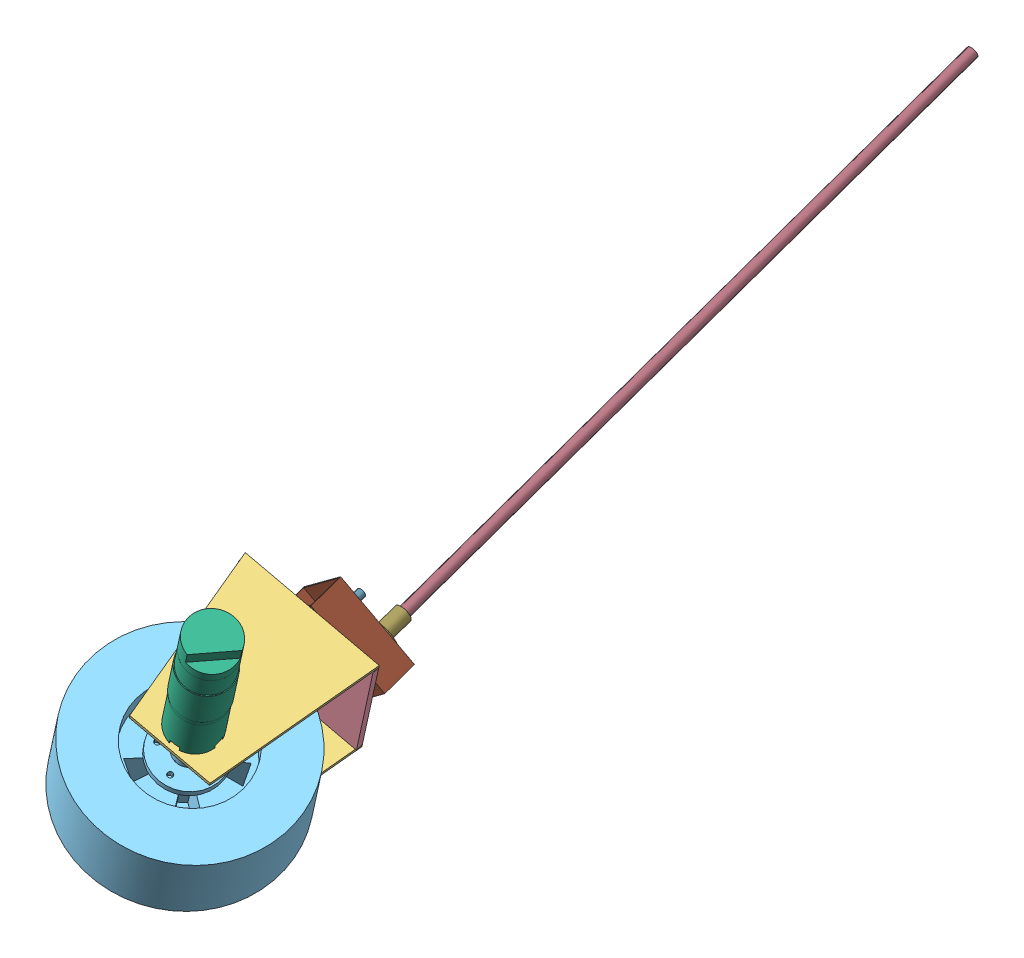
SolidWorks assembly Wheel assembly, configuration Default. Lengths in mm.
Overall size (214.24 272.73 725.65).
17 component instances, 15 part files, 37 mates.
Components (placement in the parent):
- ball bearing-1: ball bearing [Default] at (-218.0914 -76.0667 302.376) x (0.451679 0.074586 -0.889057) z (0.409963 0.867714 0.281074) size (20 20 6)
- bearing block 1-1: bearing block 1 [Default] at (-218.0914 -76.0667 302.376) x (0.911973 -0.384765 -0.142343) z (0.409963 0.867714 0.281074) size (40 40 6)
- Plate 3mm-1: Plate 3mm [Default] at (-215.3243 -77.1542 323.0439) x (0.911973 -0.384765 -0.142343) z (0.409963 0.867714 0.281074) size (100 120 3)
- Plate 5mm-1: Plate 5mm [Default] at (-195.3633 5.0237 228.7976) x (0.409963 0.867714 0.281074) z (-0.015366 0.314687 -0.949071) size (100 100 5)
- Wheel-1: Wheel [Default] at (-206.2025 -50.903 310.5272) x (0.380857 -0.442863 0.811678) z (0.409963 0.867714 0.281074) size (150 150 80)
- Plate 3mm-2: Plate 3mm [Default] at (-173.0982 12.2204 351.9945) x (0.911973 -0.384765 -0.142343) z (0.409963 0.867714 0.281074) size (100 120 3)
- DC Motor-1: DC Motor [Default] at (-171.6426 22.2453 334.2217) x (-0.695966 0.496774 -0.518505) z (-0.409963 -0.867714 -0.281074) size (37.3 37.3 158)
- shaft-1: shaft [Default] at (-220.5512 -81.273 300.6896) x (0.868806 -0.277681 -0.409963) z (0.409963 0.867714 0.281074) size (8 8 50)
- bearing block 1-2: bearing block 1 [Default] at (-195.3633 5.0237 228.7976) x (0.911973 -0.384765 -0.142343) z (0.015366 -0.314687 0.949071) size (40 40 6)
- ball bearing 6 mm-1: ball bearing 6 mm [Default] at (-195.3633 5.0237 228.7976) x (0.999879 0.002481 -0.015366) z (0.015366 -0.314687 0.949071) size (20 20 6)
- Thrust ball bearing-1: Thrust ball bearing [Default] at (-195.5016 7.8559 220.256) x (0.999879 0.002481 -0.015366) z (0.015366 -0.314687 0.949071) size (28 28 9)
- thrust ball bearing upper part-1: thrust ball bearing upper part [Default] at (-195.5938 9.744 214.5615) x (0.643715 -0.723203 -0.250217) z (0.015366 -0.314687 0.949071) size (40 40 5)
- Channel for Rod-1: Channel for Rod [Default] at (-166.8187 -18.8666 191.4384) x (-0.765111 -0.614776 -0.191456) z (-0.643715 0.723203 0.250217) size (50 25 65)
- rod weld mount-1: rod weld mount [Default] at (-179.8851 -0.4689 184.5794) x (0.620168 -0.741551 -0.255919) z (0.784319 0.592516 0.183764) size (30 25 30)
- Steel Shaft-1: Steel Shaft [Default] at (-179.9619 1.1045 179.834) x (0.222387 -0.924333 -0.310085) z (0.974837 0.215826 0.055779) size (8 500 8)
- bolt 6mm-1: bolt 6mm [Default] at (-195.225 2.1915 237.3393) x (0.639836 -0.726304 -0.251182) z (-0.015366 0.314687 -0.949071) size (11.94 10.93 63)
- nut 6mm-1: nut 6mm [Default] at (-196.0548 19.1846 186.0894) x (0.999879 0.002481 -0.015366) z (0.015366 -0.314687 0.949071) size (11.06 11.91 5)
Mates (geometry in assembly coordinates):
- Coincident5: coincident: line of Plate 3mm-1 through (-170.3396 -56.0268 202.8814) axis (-0.911973 0.384765 0.142343); line of Plate 5mm-1 through (-170.3396 -56.0268 202.8814) axis (-0.911973 0.384765 0.142343)
- Coincident6: coincident: plane of Plate 3mm-1 through (-214.0944 -74.551 323.8871) normal (0.409963 0.867714 0.281074); plane of Plate 5mm-1 through (-261.5369 -17.5504 217.1157) normal (-0.409963 -0.867714 -0.281074)
- Width1: width: plane of Plate 3mm-1 through (-261.5369 -17.5504 217.1157) normal (-0.897038 0.327795 0.296432); plane of Plate 3mm-1 through (-170.3396 -56.0268 202.8814) normal (0.902091 -0.431264 0.01562); plane of Plate 5mm-1 through (-170.3396 -56.0268 202.8814) normal (0.911973 -0.384765 -0.142343); plane of Plate 5mm-1 through (-261.5369 -17.5504 217.1157) normal (-0.911973 0.384765 0.142343)
- Coincident7: coincident: line of Plate 5mm-1 through (-220.5407 69.2211 245.2231) axis (0.911973 -0.384765 -0.142343); line of Plate 3mm-2 through (-129.3434 30.7446 230.9888) axis (-0.911973 0.384765 0.142343)
- Coincident8: coincident: plane of Plate 5mm-1 through (-220.5407 69.2211 245.2231) normal (0.409963 0.867714 0.281074); plane of Plate 3mm-2 through (-173.0982 12.2204 351.9945) normal (-0.409963 -0.867714 -0.281074)
- Width2: width: plane of Plate 3mm-2 through (-128.1135 33.3477 231.832) normal (0.902091 -0.431264 0.01562); plane of Plate 3mm-2 through (-219.3108 71.8242 246.0663) normal (-0.897038 0.327795 0.296432); plane of Plate 5mm-1 through (-261.5369 -17.5504 217.1157) normal (-0.911973 0.384765 0.142343); plane of Plate 5mm-1 through (-170.3396 -56.0268 202.8814) normal (0.911973 -0.384765 -0.142343)
- Concentric1: concentric: cylinder of bearing block 1-1 through (-215.6316 -70.8604 304.0625) axis (-0.409963 -0.867714 -0.281074) radius 10; cylinder of Plate 3mm-1 through (-214.4017 -68.2573 304.9057) axis (-0.409963 -0.867714 -0.281074) radius 4
- Coincident9: coincident: plane of bearing block 1-1 through (-215.6316 -70.8604 304.0625) normal (0.409963 0.867714 0.281074); plane of Plate 3mm-1 through (-215.3243 -77.1542 323.0439) normal (-0.409963 -0.867714 -0.281074)
- Coincident10: coincident: plane of bearing block 1-1 through (-233.5638 -69.4589 325.8907) normal (0.015366 -0.314687 0.949071); plane of Plate 3mm-1 through (-241.4536 -63.0081 328.1574) normal (0.015366 -0.314687 0.949071)
- Concentric3: concentric: cylinder of ball bearing-1 through (-215.6316 -70.8604 304.0625) axis (-0.409963 -0.867714 -0.281074) radius 10; cylinder of bearing block 1-1 through (-215.6316 -70.8604 304.0625) axis (-0.409963 -0.867714 -0.281074) radius 10
- Coincident11: coincident: plane of ball bearing-1 through (-218.0914 -76.0667 302.376) normal (-0.409963 -0.867714 -0.281074); plane of bearing block 1-1 through (-218.0914 -76.0667 302.376) normal (-0.409963 -0.867714 -0.281074)
- Concentric4: concentric: cylinder of ball bearing-1 through (-215.6316 -70.8604 304.0625) axis (-0.409963 -0.867714 -0.281074) radius 4; cylinder of Wheel-1 through (-202.1029 -42.2259 313.3379) axis (0.409963 0.867714 0.281074) radius 4
- Width3: width: plane of Wheel-1 through (-202.1029 -42.2259 313.3379) normal (-0.409963 -0.867714 -0.281074); plane of Wheel-1 through (-185.7044 -7.5173 324.5809) normal (0.409963 0.867714 0.281074); plane of Plate 3mm-2 through (-173.0982 12.2204 351.9945) normal (-0.409963 -0.867714 -0.281074); plane of Plate 3mm-1 through (-214.0944 -74.551 323.8871) normal (0.409963 0.867714 0.281074)
- Concentric5: concentric: cylinder of Plate 3mm-2 through (-172.1756 21.1173 333.8563) axis (-0.409963 -0.867714 -0.281074) radius 4; cylinder of DC Motor-1 through (-171.6426 22.2453 334.2217) axis (-0.409963 -0.867714 -0.281074) radius 4
- Coincident12: coincident: plane of Plate 3mm-2 through (-171.8683 14.8236 352.8377) normal (0.409963 0.867714 0.281074); plane of DC Motor-1 through (-172.1756 21.1173 333.8563) normal (-0.409963 -0.867714 -0.281074)
- Concentric6: concentric: cylinder of Wheel-1 through (-202.1029 -42.2259 313.3379) axis (0.409963 0.867714 0.281074) radius 4; cylinder of shaft-1 through (-200.053 -37.8873 314.7433) axis (-0.409963 -0.867714 -0.281074) radius 4
- Coincident13: coincident: plane of Wheel-1 through (-200.053 -37.8873 314.7433) normal (-0.409963 -0.867714 -0.281074); plane of shaft-1 through (-200.053 -37.8873 314.7433) normal (0.409963 0.867714 0.281074)
- Concentric7: concentric: cylinder of Plate 5mm-1 through (-195.4402 6.5971 224.0523) axis (0.015366 -0.314687 0.949071) radius 5; cylinder of bearing block 1-2 through (-195.2711 3.1356 234.492) axis (-0.015366 0.314687 -0.949071) radius 10
- Parallel1: parallel: plane of Plate 5mm-1 through (-170.3396 -56.0268 202.8814) normal (0.911973 -0.384765 -0.142343); plane of bearing block 1-2 through (-185.2309 -21.914 226.0237) normal (0.911973 -0.384765 -0.142343)
- Coincident15: coincident: plane of Plate 5mm-1 through (-195.3633 5.0237 228.7976) normal (0.015366 -0.314687 0.949071); plane of bearing block 1-2 through (-195.3633 5.0237 228.7976) normal (-0.015366 0.314687 -0.949071)
- Concentric9: concentric: cylinder of bearing block 1-2 through (-195.2711 3.1356 234.492) axis (-0.015366 0.314687 -0.949071) radius 10; cylinder of ball bearing 6 mm-1 through (-195.2711 3.1356 234.492) axis (-0.015366 0.314687 -0.949071) radius 10
- Coincident17: coincident: plane of bearing block 1-2 through (-195.2711 3.1356 234.492) normal (0.015366 -0.314687 0.949071); plane of ball bearing 6 mm-1 through (-195.2711 3.1356 234.492) normal (0.015366 -0.314687 0.949071)
- Coincident18: coincident: plane of Plate 5mm-1 through (-195.4094 5.9677 225.9504) normal (-0.015366 0.314687 -0.949071); plane of Thrust ball bearing-1 through (-195.4094 5.9677 225.9504) normal (0.015366 -0.314687 0.949071)
- Concentric10: concentric: cone of Plate 5mm-1 through (-195.4402 6.5971 224.0523) axis (0.015366 -0.314687 0.949071); cone of Thrust ball bearing-1 through (-195.4555 6.9118 223.1032) axis (0.015366 -0.314687 0.949071)
- Coincident20: coincident: plane of Thrust ball bearing-1 through (-195.5477 8.7999 217.4088) normal (-0.015366 0.314687 -0.949071); plane of thrust ball bearing upper part-1 through (-195.5477 8.7999 217.4088) normal (0.015366 -0.314687 0.949071)
- Concentric11: concentric: cone of Thrust ball bearing-1 through (-195.5016 7.8559 220.256) axis (-0.015366 0.314687 -0.949071); cone of thrust ball bearing upper part-1 through (-195.517 8.1705 219.3069) axis (-0.015366 0.314687 -0.949071)
- Coincident25: coincident: plane of thrust ball bearing upper part-1 through (-195.5938 9.744 214.5615) normal (-0.015366 0.314687 -0.949071); plane of Channel for Rod-1 through (-189.3404 39.5774 224.3523) normal (0.015366 -0.314687 0.949071)
- Coincident26: coincident: line of thrust ball bearing upper part-1 through (-193.1659 36.5036 223.395) axis (-0.765111 -0.614776 -0.191456); line of Channel for Rod-1 through (-227.5959 8.8386 214.7795) axis (0.765111 0.614776 0.191456)
- Width4: width: plane of thrust ball bearing upper part-1 through (-223.6935 10.3391 220.4821) normal (-0.765111 -0.614776 -0.191456); plane of thrust ball bearing upper part-1 through (-193.0891 34.9301 228.1404) normal (0.765111 0.614776 0.191456); plane of Channel for Rod-1 through (-189.7245 47.4446 200.6255) normal (0.765111 0.614776 0.191456); plane of Channel for Rod-1 through (-227.98 16.7058 191.0527) normal (-0.765111 -0.614776 -0.191456)
- Concentric12: concentric: circle of Channel for Rod-1; circle of rod weld mount-1
- Coincident28: coincident: plane of Channel for Rod-1 through (-189.7245 47.4446 200.6255) normal (-0.015366 0.314687 -0.949071); plane of rod weld mount-1 through (-179.8851 -0.4689 184.5794) normal (0.015366 -0.314687 0.949071)
- Concentric13: concentric: cylinder of rod weld mount-1 through (-180.2692 7.3983 160.8526) axis (0.015366 -0.314687 0.949071) radius 4; cylinder of Steel Shaft-1 through (-187.6447 158.448 -294.7016) axis (0.015366 -0.314687 0.949071) radius 4
- Coincident29: coincident: plane of rod weld mount-1 through (-179.9619 1.1045 179.834) normal (-0.015366 0.314687 -0.949071); plane of Steel Shaft-1 through (-179.9619 1.1045 179.834) normal (0.015366 -0.314687 0.949071)
- Concentric16: concentric: cylinder of ball bearing 6 mm-1 through (-195.2711 3.1356 234.492) axis (-0.015366 0.314687 -0.949071) radius 3; cylinder of bolt 6mm-1 through (-196.1931 22.0168 177.5478) axis (0.015366 -0.314687 0.949071) radius 3
- Coincident30: coincident: plane of ball bearing 6 mm-1 through (-195.2711 3.1356 234.492) normal (0.015366 -0.314687 0.949071); plane of bolt 6mm-1 through (-195.2711 3.1356 234.492) normal (-0.015366 0.314687 -0.949071)
- Concentric17: concentric: cylinder of bolt 6mm-1 through (-196.1931 22.0168 177.5478) axis (0.015366 -0.314687 0.949071) radius 3; cylinder of nut 6mm-1 through (-195.978 17.6112 190.8348) axis (-0.015366 0.314687 -0.949071) radius 3
- Coincident31: coincident: plane of Channel for Rod-1 through (-189.7245 47.4446 200.6255) normal (-0.015366 0.314687 -0.949071); plane of nut 6mm-1 through (-195.978 17.6112 190.8348) normal (0.015366 -0.314687 0.949071)
